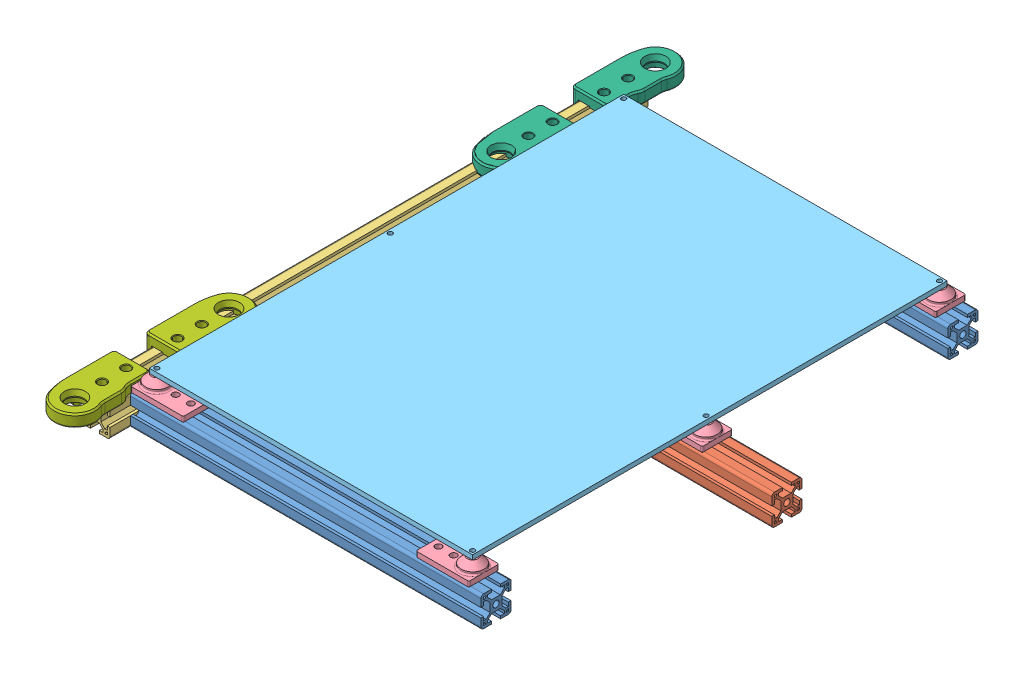
SolidWorks assembly Bed, configuration Default. Lengths in mm.
Overall size (294.84 33 411.2).
13 component instances, 7 part files, 33 mates.
Components (placement in the parent):
- 232mm2020-1: 232mm2020 [Default] at (-152.3553 73.7145 -117.8353) x (0 0 1) z (-1 0 0) size (20 20 232)
- 270mm2020-1: 270mm2020 [Default] at (-114.3553 73.7145 36.6647) x (0 0 1) z (-1 0 0) size (20 20 270)
- 356mm2020-1: 356mm2020 [Default] at (108.6447 73.7145 361.6647) size (20 20 356)
- bed_mount-1: bed_mount [Default] at (118.6447 83.7145 201.1647) x (0 0 1) z (0 1 0) size (20 35 10)
- 232mm2020-2: 232mm2020 [Default] at (-152.3553 73.7145 191.1647) x (0 0 1) z (-1 0 0) size (20 20 232)
- bed_pcb-1: bed_pcb [Default] at (337.6447 93.7145 -120.3353) x (0 0 -1) z (1 0 0) size (314 3 214)
- bed_mount-2: bed_mount [Default] at (342.6447 83.7145 -127.8353) x (0 0 -1) z (0 1 0) size (20 35 10)
- bed_mount-3: bed_mount [Default] at (342.6447 83.7145 181.1647) x (0 0 -1) z (0 1 0) size (20 35 10)
- bed_mount-4: bed_mount [Default] at (118.6447 83.7145 -107.8353) x (0 0 1) z (0 1 0) size (20 35 10)
- bed_mount-5: bed_mount [Default] at (118.6447 83.7145 46.6647) x (0 0 1) z (0 1 0) size (20 35 10)
- bed_mount-6: bed_mount [Default] at (342.6447 83.7145 26.6647) x (0 0 -1) z (0 1 0) size (20 35 10)
- Z_Bed_Left-1: Z_Bed_Left [Default] at (-27.9029 415.2227 -260.8985) x (1 0 0) z (0 1 0) size (28.54 129 16.03)
- Z_Bed_Right-1: Z_Bed_Right [Default] at (-27.9029 415.2227 21.2967) x (1 0 0) z (0 1 0) size (28.54 129 16.03)
Mates (geometry in assembly coordinates):
- Coincident1: coincident anti-aligned: plane of 356mm2020-1 through (118.6447 69.1193 361.6647) normal (1 0 0); plane of 232mm2020-2 through (118.6447 73.7145 191.1647) normal (-1 0 0)
- Coincident2: coincident aligned: plane of 356mm2020-1 through (113.2399 83.7145 361.6647) normal (0 1 0); plane of 232mm2020-2 through (-152.3553 83.7145 195.7598) normal (0 1 0)
- Coincident3: coincident anti-aligned: plane of 232mm2020-1 through (118.6447 73.7145 -117.8353) normal (-1 0 0); plane of 356mm2020-1 through (118.6447 81.9145 361.6647) normal (1 0 0)
- Coincident4: coincident aligned: plane of 232mm2020-1 through (-152.3553 83.7145 -126.0353) normal (0 1 0); plane of 356mm2020-1 through (113.2399 83.7145 361.6647) normal (0 1 0)
- Coincident5: coincident anti-aligned: plane of 270mm2020-1 through (118.6447 73.7145 36.6647) normal (-1 0 0); plane of 356mm2020-1 through (118.6447 81.9145 361.6647) normal (1 0 0)
- Coincident6: coincident aligned: plane of 270mm2020-1 through (-114.3553 83.7145 28.4647) normal (0 1 0); plane of 356mm2020-1 through (113.2399 83.7145 361.6647) normal (0 1 0)
- Width1: width aligned: plane of 270mm2020-1 through (-114.3553 81.9145 46.6647) normal (0 0 1); plane of 270mm2020-1 through (-114.3553 78.3096 26.6647) normal (0 0 -1); plane of 356mm2020-1 through (108.6447 73.7145 214.6647) normal (0 0 1); plane of 356mm2020-1 through (108.6447 73.7145 -141.3353) normal (0 0 -1)
- Coincident12: coincident anti-aligned: plane of bed_mount-1 through (118.6447 83.7145 201.1647) normal (0 -1 0); plane of 232mm2020-2 through (-152.3553 83.7145 195.7598) normal (0 1 0)
- Coincident13: coincident aligned: plane of bed_mount-1 through (118.6447 87.7145 201.1647) normal (0 0 1); plane of 232mm2020-2 through (-152.3553 81.9145 201.1647) normal (0 0 1)
- Concentric1: concentric anti-aligned: cylinder of bed_mount-1 through (126.1447 86.7145 191.1647) axis (0 1 0) radius 2.3; cylinder of bed_pcb-1 through (126.1447 96.7145 191.1647) axis (0 -1 0) radius 1.5
- Parallel3: parallel aligned: plane of 232mm2020-2 through (-152.3553 81.9145 201.1647) normal (0 0 1); plane of bed_pcb-1 through (123.6447 96.7145 193.6647) normal (0 0 1)
- Coincident15: coincident anti-aligned: circle of bed_mount-1; plane of bed_pcb-1 through (337.6447 93.7145 -120.3353) normal (0 -1 0)
- Coincident16: coincident anti-aligned: plane of 232mm2020-2 through (-152.3553 83.7145 195.7598) normal (0 1 0); plane of bed_mount-3 through (342.6447 83.7145 181.1647) normal (0 -1 0)
- Coincident17: coincident aligned: plane of 232mm2020-2 through (-152.3553 81.9145 201.1647) normal (0 0 1); plane of bed_mount-3 through (342.6447 87.7145 201.1647) normal (0 0 1)
- Coincident18: coincident anti-aligned: plane of 232mm2020-1 through (-152.3553 83.7145 -113.2402) normal (0 1 0); plane of bed_mount-4 through (118.6447 83.7145 -107.8353) normal (0 -1 0)
- Coincident19: coincident aligned: plane of 232mm2020-1 through (-152.3553 78.3096 -127.8353) normal (0 0 -1); plane of bed_mount-4 through (118.6447 87.7145 -127.8353) normal (0 0 -1)
- Concentric2: concentric anti-aligned: cylinder of bed_pcb-1 through (126.1447 96.7145 -117.8353) axis (0 -1 0) radius 1.5; cylinder of bed_mount-4 through (126.1447 86.7145 -117.8353) axis (0 1 0) radius 2.3
- Concentric3: concentric anti-aligned: cylinder of bed_pcb-1 through (335.1447 96.7145 191.1647) axis (0 -1 0) radius 1.5; cylinder of bed_mount-3 through (335.1447 86.7145 191.1647) axis (0 1 0) radius 2.3
- Coincident20: coincident aligned: plane of 232mm2020-1 through (-152.3553 81.9145 -107.8353) normal (0 0 1); plane of bed_mount-2 through (342.6447 87.7145 -107.8353) normal (0 0 1)
- Coincident21: coincident: plane of 232mm2020-1 through (-152.3553 83.7145 -126.0353) normal (0 1 0); line of bed_mount-2 through (308.6447 83.7145 -127.2353) axis (1 0 0)
- Concentric4: concentric aligned: circle of bed_pcb-1; cylinder of bed_mount-2 through (335.1447 86.7145 -117.8353) axis (0 1 0) radius 2.3
- Width2: width anti-aligned: plane of 232mm2020-1 through (-152.3553 78.3096 -127.8353) normal (0 0 -1); plane of 232mm2020-2 through (-152.3553 81.9145 201.1647) normal (0 0 1); plane of 356mm2020-1 through (108.6447 73.7145 214.6647) normal (0 0 1); plane of 356mm2020-1 through (108.6447 73.7145 -141.3353) normal (0 0 -1)
- Coincident22: coincident anti-aligned: plane of 356mm2020-1 through (118.6447 81.9145 361.6647) normal (1 0 0); plane of bed_mount-4 through (118.6447 87.7145 -107.8353) normal (-1 0 0)
- Coincident23: coincident anti-aligned: plane of 270mm2020-1 through (-114.3553 83.7145 41.2598) normal (0 1 0); plane of bed_mount-6 through (342.6447 83.7145 26.6647) normal (0 -1 0)
- Coincident24: coincident aligned: plane of 270mm2020-1 through (-114.3553 81.9145 46.6647) normal (0 0 1); plane of bed_mount-6 through (342.6447 87.7145 46.6647) normal (0 0 1)
- Concentric5: concentric anti-aligned: cylinder of bed_pcb-1 through (335.1447 103.7145 36.6647) axis (0 -1 0) radius 1.5; cylinder of bed_mount-6 through (335.1447 86.7145 36.6647) axis (0 1 0) radius 2.3
- Coincident25: coincident anti-aligned: plane of 270mm2020-1 through (-114.3553 83.7145 41.2598) normal (0 1 0); plane of bed_mount-5 through (118.6447 83.7145 46.6647) normal (0 -1 0)
- Coincident26: coincident aligned: plane of 270mm2020-1 through (-114.3553 81.9145 46.6647) normal (0 0 1); plane of bed_mount-5 through (118.6447 87.7145 46.6647) normal (0 0 1)
- Concentric6: concentric anti-aligned: cylinder of bed_pcb-1 through (126.1447 103.7145 36.6647) axis (0 -1 0) radius 1.5; cylinder of bed_mount-5 through (126.1447 86.7145 36.6647) axis (0 1 0) radius 2.3
- Coincident27: coincident anti-aligned: plane of 356mm2020-1 through (100.4447 83.7145 361.6647) normal (0 1 0); plane of Z_Bed_Left-1 through (108.8447 83.7145 -128.5776) normal (0 -1 0)
- Coincident28: coincident anti-aligned: plane of 356mm2020-1 through (98.6447 78.3096 361.6647) normal (-1 0 0); plane of Z_Bed_Left-1 through (98.6447 89.7145 -147.0084) normal (1 0 0)
- Coincident29: coincident anti-aligned: plane of 356mm2020-1 through (113.2399 83.7145 361.6647) normal (0 1 0); plane of Z_Bed_Right-1 through (108.8447 83.7145 200.6176) normal (0 -1 0)
- Coincident30: coincident anti-aligned: plane of 356mm2020-1 through (98.6447 78.3096 361.6647) normal (-1 0 0); plane of Z_Bed_Right-1 through (98.6447 89.7145 219.0484) normal (1 0 0)
